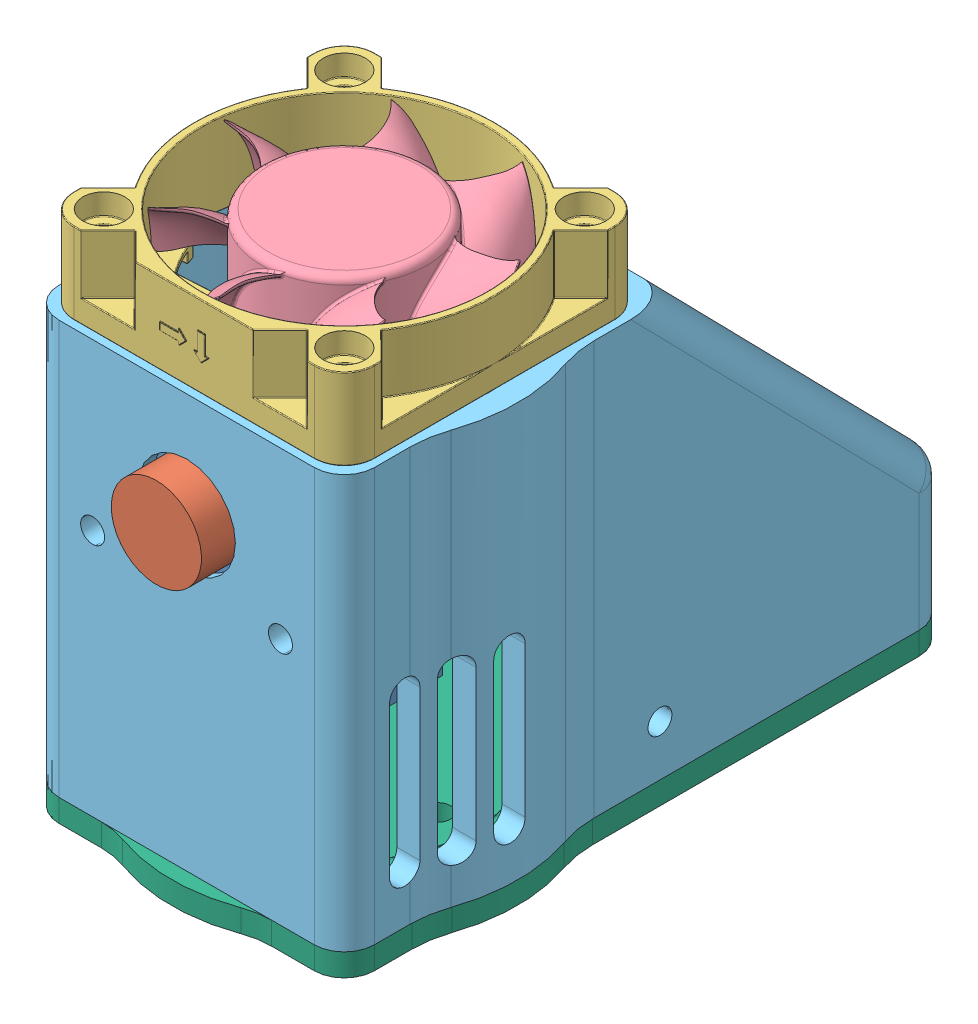
SolidWorks assembly LCheapo, configuration Default. Lengths in mm.
Overall size (52.6 68.81 86).
7 component instances, 6 part files, 7 mates.
Components (placement in the parent):
- Laser Heatsink-1: Laser Heatsink [Default] at (4.4862 48 -3.5) x (1 0 0) z (0 1 0) size (33 20 26)
- Laser-1: Laser [Default] at (20.9862 41 4) x (0.809634 0.586936 0) z (-0.586936 0.809634 0) size (12 32 12)
- Jamicon_KF0410-01-1: Jamicon_KF0410-01 [По умолчанию] at (21 58 -21) x (1 0 0) z (0 1 0) size (52.6 52.59 10.82)
  - Jamicon_KF0410-01_Case-1: Jamicon_KF0410-01_Case [Default] at origin size (40.01 40.11 10.81)
  - Jamicon_KF0410-01_Rotor-1: Jamicon_KF0410-01_Rotor [Default] at (0 0 -1) x (0.720673 0.693275 0) z (0 0 1) size (37.4 37 9.12)
- LCheapo Case-1: LCheapo Case [Default] at origin size (46.15 55 80.5)
- Case Backplate-1: Case Backplate [Default] at (0 -3 0) size (46 14.85 82.5)
Mates (geometry in assembly coordinates):
- Concentric1: concentric aligned: circle of Laser Heatsink-1; circle of Laser-1
- Concentric4: concentric anti-aligned: circle of Jamicon_KF0410-01-1/Jamicon_KF0410-01_Case-1; circle of LCheapo Case-1
- Concentric5: concentric anti-aligned: circle of Jamicon_KF0410-01-1/Jamicon_KF0410-01_Case-1; circle of LCheapo Case-1
- Coincident3: coincident anti-aligned: plane of Jamicon_KF0410-01-1/Jamicon_KF0410-01_Case-1 through (9.5513 55 -2.0554) normal (0 -1 0); plane of LCheapo Case-1 through (21 55 -21) normal (0 1 0)
- Distance1: distance = 7.5 mm aligned: plane of Laser Heatsink-1 through (4.4862 48 -3.5) normal (0 0 1); plane of Laser-1 through (20.9862 41 4) normal (0 0 1)
- Coincident5: coincident anti-aligned: plane of Laser Heatsink-1 through (4.4862 48 -3.5) normal (0 0 1); plane of LCheapo Case-1 through (36 47 -3.5) normal (0 0 -1)
- Distance2: distance = 2 mm anti-aligned: plane of Laser Heatsink-1 through (37.4862 48 -23.5) normal (0 1 0); plane of LCheapo Case-1 through (36 50 -3.5) normal (0 -1 0)
